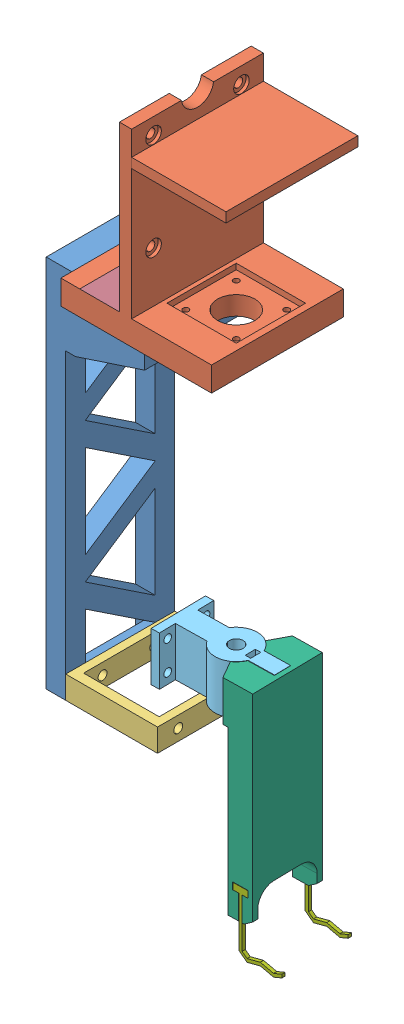
SolidWorks assembly replica-v004, configuration Default. Lengths in mm.
Overall size (132.39 427.1 81).
9 component instances, 7 part files, 19 mates.
Components (placement in the parent):
- ladder-toolhead-v002-1: ladder-toolhead-v002 [Default] at (-38.579 -107.7624 20.3051) size (60.5 230 67)
- bracket-toolhead-v002-1: bracket-toolhead-v002 [Default] at (-38.579 -107.4624 20.3051) size (101.5 116 81)
- bottom-toolhead-v002-1: bottom-toolhead-v002 [Default] at (-38.579 -107.7624 20.3051) size (56.4 14 67)
- triangle-support-1: triangle-support [Default] at (-51.5128 121.9844 17.3051) x (0.008726 -0.999962 0) z (-0.999962 -0.008726 0) size (29 6 29)
- triangle-support-2: triangle-support [Default] at (-51.4791 122.2365 54.8051) x (0.000038 -1 0) z (-1 -0.000038 0) size (29 6 29)
- cartridge-v002-1: cartridge-v002 [Default] at (-30.4737 -89.0909 20.9103) x (0.99985 0 -0.017294) z (0.017294 0 0.99985) size (63 30 34)
- forklift-body-1: forklift-body [Default] at (26.6344 -84.0909 20.0726) x (0.99985 0 -0.017294) z (0.017294 0 0.99985) size (23.95 125 43.5)
- forklift-arm-1: forklift-arm [Default] at (27.6104 -199.6069 41.809) x (-0.99985 0 0.017294) z (0 -1 0) size (29.5 2 38.38)
- forklift-arm-2: forklift-arm [Default] at (26.8927 -199.6069 0.3152) x (-0.99985 0 0.017294) z (0 -1 0) size (29.5 2 38.38)
Mates (geometry in assembly coordinates):
- Concentric1: concentric aligned: cylinder of ladder-toolhead-v002-1 through (-78.779 -100.7624 36.1551) axis (1 0 0) radius 2.75; cylinder of bottom-toolhead-v002-1 through (-78.779 -100.7624 36.1551) axis (1 0 0) radius 2.75
- Concentric2: concentric aligned: cylinder of ladder-toolhead-v002-1 through (-78.779 -100.7624 4.4551) axis (1 0 0) radius 2.75; cylinder of bottom-toolhead-v002-1 through (-78.779 -100.7624 4.4551) axis (1 0 0) radius 2.75
- Coincident1: coincident anti-aligned: plane of ladder-toolhead-v002-1 through (-66.779 92.2376 -1.1949) normal (1 0 0); plane of bottom-toolhead-v002-1 through (-66.779 -93.7624 -13.1949) normal (-1 0 0)
- Coincident2: coincident anti-aligned: plane of ladder-toolhead-v002-1 through (-18.279 112.2376 -13.1949) normal (0 -1 0); plane of bracket-toolhead-v002-1 through (-17.779 112.2376 20.3051) normal (0 1 0)
- Coincident4: coincident anti-aligned: plane of ladder-toolhead-v002-1 through (-38.579 -93.7624 -13.1949) normal (0 0 -1); plane of bracket-toolhead-v002-1 through (-17.779 -107.4624 -13.1949) normal (0 0 1)
- Coincident5: coincident anti-aligned: plane of bracket-toolhead-v002-1 through (-38.579 -107.4624 17.3051) normal (0 0 1); plane of triangle-support-1 through (-51.5128 121.9844 17.3051) normal (0 0 -1)
- Coincident6: coincident aligned: line of bracket-toolhead-v002-1 through (-22.479 118.2376 20.7051) axis (0 0 -1); line of triangle-support-1 through (-22.479 118.2376 20.3051) axis (0 0 -1)
- Coincident7: coincident anti-aligned: plane of bracket-toolhead-v002-1 through (-38.579 -107.4624 54.8051) normal (0 0 1); plane of triangle-support-2 through (-51.4791 122.2365 54.8051) normal (0 0 -1)
- Coincident8: coincident aligned: line of bracket-toolhead-v002-1 through (-22.479 118.2376 58.2051) axis (0 0 -1); line of triangle-support-2 through (-22.479 118.2376 57.8051) axis (0 0 -1)
- Concentric3: concentric anti-aligned: cylinder of bracket-toolhead-v002-1 through (4.521 75.0107 20.3051) axis (0 1 0) radius 11.5; cylinder of cartridge-v002-1 through (4.521 -59.0909 20.3051) axis (0 -1 0) radius 4.25
- Coincident9: coincident anti-aligned: plane of ladder-toolhead-v002-1 through (-62.779 -107.7624 20.3051) normal (1 0 0); plane of bracket-toolhead-v002-1 through (-62.779 122.5376 20.3051) normal (-1 0 0)
- Coincident10: coincident aligned: plane of cartridge-v002-1 through (4.521 -59.0909 20.3051) normal (0 1 0); plane of forklift-body-1 through (26.6344 -59.0909 20.0726) normal (0 1 0)
- Coincident11: coincident anti-aligned: plane of cartridge-v002-1 through (32.4304 -59.0909 14.8216) normal (-0.014977 0.5 -0.865896); plane of forklift-body-1 through (32.5444 -59.0909 14.8196) normal (0.014977 -0.5 0.865896)
- Coincident12: coincident anti-aligned: plane of forklift-body-1 through (26.9759 -169.1909 39.8197) normal (0 1 0); plane of forklift-arm-1 through (33.075 -169.1909 39.7142) normal (0 -1 0)
- Coincident13: coincident anti-aligned: plane of forklift-body-1 through (26.9759 -84.0909 39.8197) normal (0.017294 0 0.99985); plane of forklift-arm-1 through (27.5758 -199.6069 39.8093) normal (-0.017294 0 -0.99985)
- Coincident14: coincident anti-aligned: plane of forklift-body-1 through (33.075 -84.0909 39.7142) normal (-0.99985 0 0.017294); plane of forklift-arm-1 through (33.075 -165.1909 39.7142) normal (0.99985 0 -0.017294)
- Coincident15: coincident anti-aligned: plane of forklift-body-1 through (26.2928 -84.0909 0.3256) normal (-0.017294 0 -0.99985); plane of forklift-arm-2 through (26.8927 -199.6069 0.3152) normal (0.017294 0 0.99985)
- Coincident16: coincident anti-aligned: plane of forklift-body-1 through (26.2928 -169.1909 0.3256) normal (0 1 0); plane of forklift-arm-2 through (32.3573 -169.1909 -1.7796) normal (0 -1 0)
- Coincident17: coincident anti-aligned: plane of forklift-body-1 through (32.3919 -59.0909 0.2201) normal (-0.99985 0 0.017294); plane of forklift-arm-2 through (32.3573 -165.1909 -1.7796) normal (0.99985 0 -0.017294)
